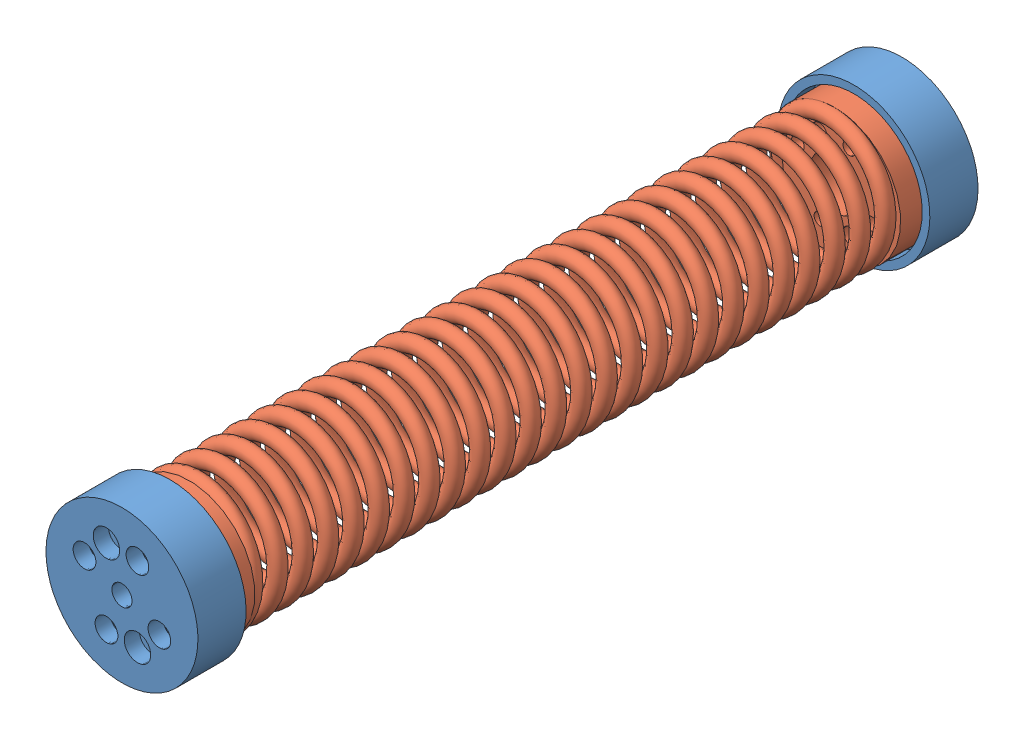
SolidWorks assembly Montagem mola, configuration Valor predeterminado. Lengths in mm.
Overall size (78.41 78.41 308.04).
3 component instances, 2 part files, 5 mates.
Components (placement in the parent):
- Suporte_mola-1: Suporte_mola [Valor predeterminado] at (-99.3897 -59.5088 88.9464) x (0.923728 0.383049 0) z (0 0 1) size (60 60 19.02)
- Mola 30 cm-1: Mola 30 cm [Valor predeterminado] at (-99.3897 -59.5088 377.9664) x (-0.923728 -0.383049 0) z (0.383049 -0.923728 0) size (52.37 285 54.99)
- Suporte_mola-2: Suporte_mola [Valor predeterminado] at (-99.3897 -59.5088 396.9864) x (-0.923728 -0.383049 0) z (0 0 -1) size (60 60 19.02)
Mates (geometry in assembly coordinates):
- Concêntrico1: concentric aligned: cylinder of Suporte_mola-1 through (-99.3897 -59.5088 100.4664) axis (0 0 1) radius 27; cylinder of Mola 30 cm-1 through (-99.3897 -59.5088 100.4664) axis (0 0 1) radius 26
- Coincidente1: coincident anti-aligned: plane of Suporte_mola-1 through (-99.3897 -59.5088 100.4664) normal (0 0 1); plane of Mola 30 cm-1 through (-99.3897 -59.5088 100.4664) normal (0 0 -1)
- Coincidente5: coincident anti-aligned: plane of Mola 30 cm-1 through (-99.3897 -59.5088 385.4664) normal (0 0 1); plane of Suporte_mola-2 through (-99.3897 -59.5088 385.4664) normal (0 0 -1)
- Concêntrico2: concentric anti-aligned: cylinder of Mola 30 cm-1 through (-99.3897 -59.5088 370.4664) axis (0 0 1) radius 26; cylinder of Suporte_mola-2 through (-99.3897 -59.5088 385.4664) axis (0 0 -1) radius 27
- Concêntrico3: concentric aligned: cylinder of Mola 30 cm-1 through (-105.5185 -44.7292 370.4664) axis (0 0 1) radius 3; circle of Suporte_mola-2
